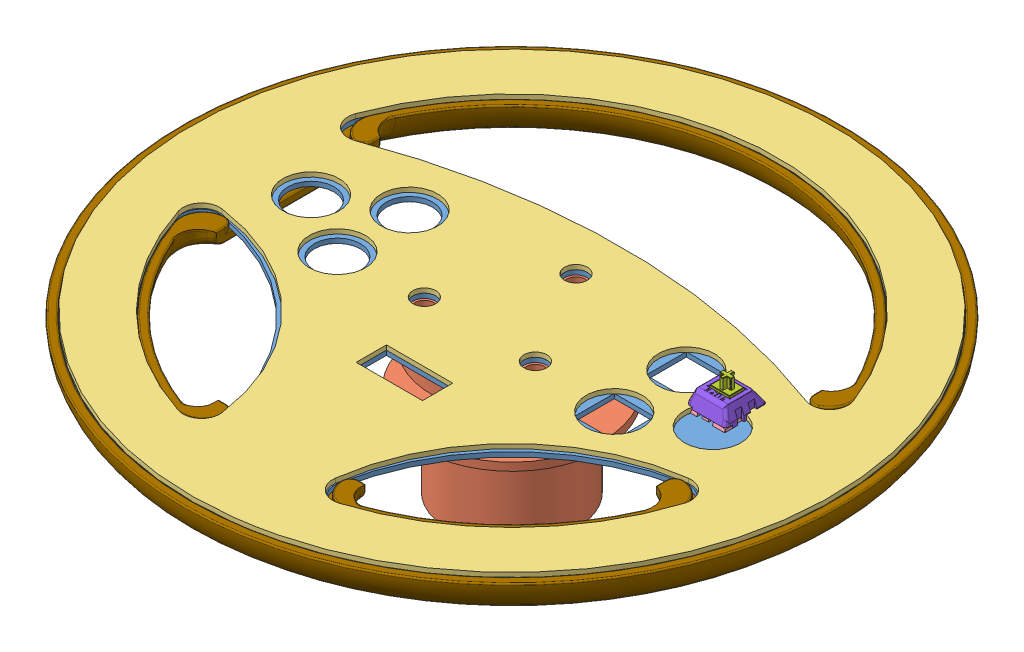
SolidWorks assembly SteeringWheelAssem, configuration Default. Lengths in mm.
Overall size (259.2 60.2 259.2).
11 component instances, 10 part files, 9 mates.
Components (placement in the parent):
- CF1-1: CF1 [Default] at (31.2672 94.6298 152.6676) size (222.25 1.59 222.25)
- Quick Release (Non-Functional)-1: Quick Release (Non-Functional) [Default] at (31.2672 94.6298 152.6676) x (-0.5 0 -0.866025) z (-0.866025 0 0.5) size (63.5 54.37 63.5)
- CF2-1: CF2 [Default] at (31.6459 96.2173 154.6997) x (0.983076 0 -0.183201) z (0.183201 0 0.983076) size (222.25 1.59 222.25)
- Kailh Polia_1.step-1: Kailh Polia_1.step [Default] at (96.2922 96.2173 143.0656) x (0 0 1) z (0 1 0) size (15.6 14.12 18.55) (hidden)
  - Housing.step-1: Housing.step [Default] at origin size (15.6 13.95 12.55)
  - ThickContact.step-1: ThickContact.step [Default] at origin size (1.42 6.81 10) (hidden)
  - SpringContact.step-1: SpringContact.step [Default] at origin size (2.16 9.4 13.5) (hidden)
  - Stem.step-1: Stem.step [Default] at origin size (6.51 8.7 13.55)
  - Lid.step-1: Lid.step [Default] at origin size (14.82 14.12 11.32)
- Part2^SteeringWheelAssem-1: Part2^SteeringWheelAssem [Default] at origin (virtual)
- BackTPU-1: BackTPU [Default] at (31.2672 96.6141 152.6676) x (0.999998 0 -0.001796) z (-0.001796 0 -0.999998) size (228.59 43.48 228.58)
Mates (geometry in assembly coordinates):
- Concentric3: concentric anti-aligned: cylinder of CF1-1 through (31.2672 96.2173 130.4426) axis (0 -1 0) radius 3.9688; cylinder of Quick Release (Non-Functional)-1 through (31.2672 81.9298 130.4426) axis (0 1 0) radius 3.175
- Concentric4: concentric anti-aligned: cylinder of CF1-1 through (12.0198 96.2173 163.7801) axis (0 -1 0) radius 3.9688; cylinder of Quick Release (Non-Functional)-1 through (12.0198 81.9298 163.7801) axis (0 1 0) radius 3.175
- Coincident8: coincident anti-aligned: plane of CF1-1 through (31.2672 94.6298 152.6676) normal (0 -1 0); plane of Quick Release (Non-Functional)-1 through (31.2672 94.6298 152.6676) normal (0 1 0)
- Coincident11: coincident anti-aligned: plane of CF1-1 through (31.2672 96.2173 152.6676) normal (0 1 0); plane of Kailh Polia_1.step-1/Housing.step-1 through (101.1047 96.2173 150.2226) normal (0 -1 0)
- Concentric8: concentric aligned: circle of CF1-1; circle of BackTPU-1
- Coincident13: coincident anti-aligned: plane of CF1-1 through (31.2672 94.6298 152.6676) normal (0 -1 0); plane of BackTPU-1 through (31.2672 94.6298 152.6676) normal (0 1 0)
- Lock1: lock: unknown of CF1-1; unknown of BackTPU-1
- Coincident16: coincident anti-aligned: plane of CF1-1 through (31.2672 96.2173 152.6676) normal (0 1 0); plane of CF2-1 through (31.2672 96.2173 152.6676) normal (0 -1 0)
- Coincident17: coincident aligned: circle of CF1-1; circle of CF2-1
